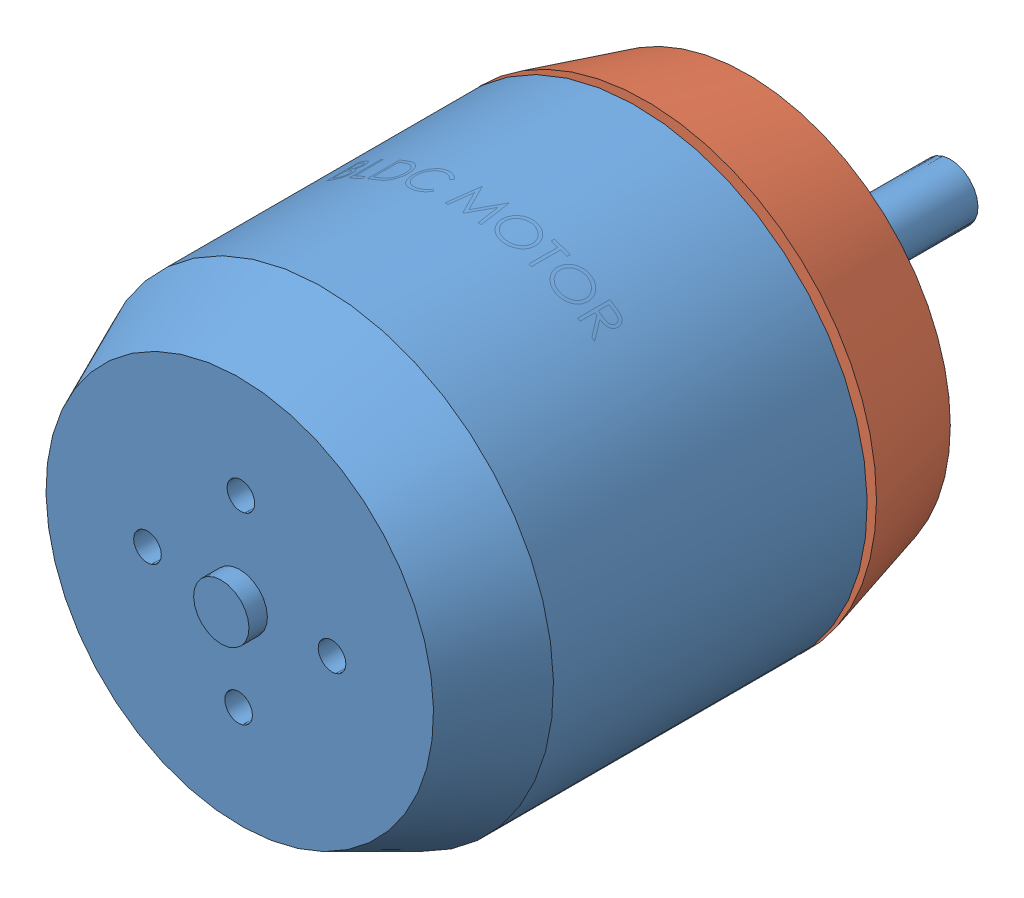
SolidWorks assembly Bldc T motor Ass, configuration Default. Lengths in mm.
Overall size (51.01 51.01 79).
2 component instances, 2 part files, 2 mates.
Components (placement in the parent):
- Driving motor Rotating component (T4130)-1: Driving motor Rotating component (T4130) [Default] at (61.2954 27.3923 47.3234) x (0.99979 0.020493 0) z (0 0 1) size (50 50 79)
- Driving motor Fixed component (T4130)-2: Driving motor Fixed component (T4130) [Default] at (47.0306 27.0999 122.3902) size (50 50 11)
Mates (geometry in assembly coordinates):
- Concentric1: concentric: cylinder of Driving motor Rotating component (T4130)-1 through (47.0306 27.0999 -2.9994) axis (0 0 1) radius 3; cylinder of Driving motor Fixed component (T4130)-2 through (47.0306 27.0999 28.3902) axis (0 0 -1) radius 3
- Distance1: distance = 1 mm anti-aligned: plane of Driving motor Rotating component (T4130)-1 through (72.0254 27.6123 29.3902) normal (0 0 -1); plane of Driving motor Fixed component (T4130)-2 through (72.0306 27.0999 28.3902) normal (0 0 1)
